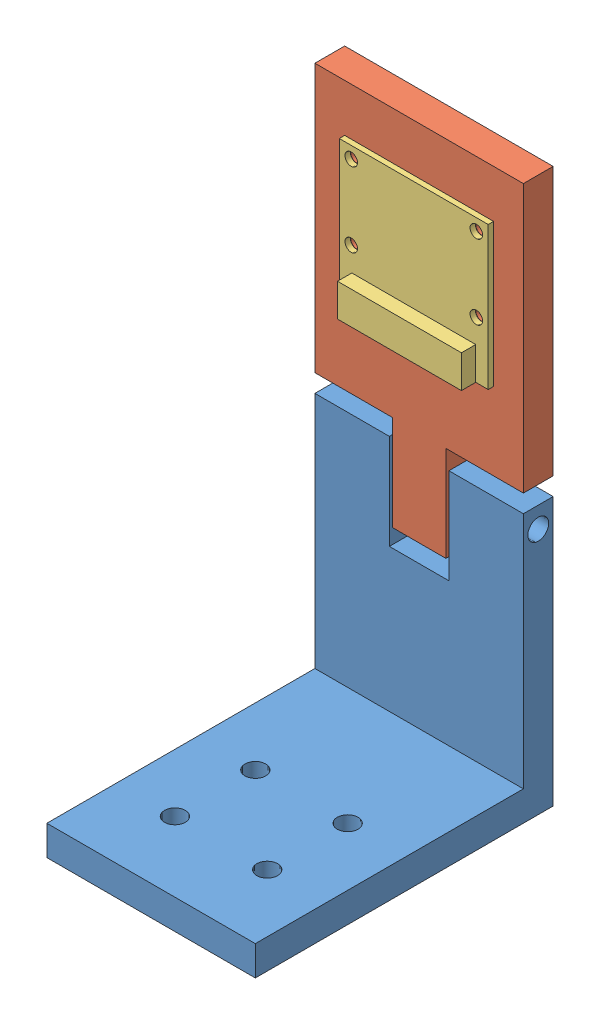
SolidWorks assembly Assem1, configuration Default. Lengths in mm.
Overall size (35 94.28 65.63).
10 component instances, 8 part files, 9 mates.
Components (placement in the parent):
- Camera mount bottom-1: Camera mount bottom [Default] at (-23.7366 -18.3036 25.44) size (35 45 50)
- Part3^New Camera Mount-1: Part3^New Camera Mount [Default] at (-16.9354 -4.185 34.7622) x (0 -0.265804 -0.964027) z (1 0 0) size (21.03 60.13 35) (virtual)
- RasPi_Camera-1: RasPi_Camera [FOV] at (-6.2366 52.1964 -20.1117) x (1 0 0) z (0 1 0) size (25 8.25 24)
  - RasPi_Camera_Board-1: RasPi_Camera_Board [Standard] at (0 -0.5517 0) x (-1 0 0) z (0 0 -1) size (25 3.5 24)
  - OVA5647-2: OVA5647 [FOV] at (0.0315 -0.3517 0.0586) size (8 5.3 16.75)
    - OVA5647-1: OVA5647 [Standard] at (0.32 0 -0.175) size (8 0.68 8)
    - OVA5647_Housing-1: OVA5647_Housing [Standard] at origin size (8 3.95 8)
    - OVA5647_IR-Glas-1: OVA5647_IR-Glas [Standard] at (0 0.95 0) x (-1 0 0) z (0 0 1) size (6.3 0.35 6.3)
    - OVA5647_Lens-1: OVA5647_Lens [FOV] at (0 3.95 0) size (6 3.35 6)
    - OVA5647_Pigtail-1: OVA5647_Pigtail [Standard] at origin size (8 1.3 16.75)
Mates (geometry in assembly coordinates):
- InPlace1: in place: plane of Camera mount bottom-1 through (-11.2366 26.6964 -24.56) normal (1 0 0); plane of ? through (-11.2366 0 0) normal (1 0 0); moOrthogonalPlaneRef_w of Camera mount bottom-1 through (-11.2366 26.6964 -24.56) normal (1 0 0); plane of ? through (-11.2366 0 0) normal (0 1 0); plane of Camera mount bottom-1 through (-11.2366 26.6964 -24.56) normal (1 0 0); plane of ? through (-11.2366 0 0) normal (0 0 -1); plane of Camera mount bottom-1 through (-11.2366 26.6964 -24.56) normal (1 0 0); unknown of Part3^New Camera Mount-1
- Coincident1: coincident aligned: plane of ?; plane of ?
- Coincident2: coincident aligned: moOrthogonalPlaneRef_w of Camera mount bottom-1 through (-11.2366 -18.3036 25.44) normal (0 1 0); plane of Part3^Assem1-1
- Coincident3: coincident anti-aligned: moOrthogonalPlaneRef_w of Camera mount bottom-1 through (-11.2366 -18.3036 25.44) normal (0 0 1); plane of Part3^Assem1-1
- Concentric1: concentric aligned: cylinder of Camera mount bottom-1 through (11.2634 23.1964 -22.06) axis (-1 0 0) radius 1.75; cylinder of Part3^Assem1-1 through (11.2644 23.1964 -22.06) axis (-1 0 0) radius 1.75
- Width2: width anti-aligned: plane of Camera mount bottom-1 through (-1.2366 26.6964 -19.56) normal (-1 0 0); plane of Part3^Assem1-1 through (-11.2366 26.6964 -24.56) normal (1 0 0); plane of Camera mount bottom-1 through (-1.7366 13.6964 -94.8878) normal (1 0 0); plane of Part3^Assem1-1 through (-10.7366 29.6964 -94.8878) normal (-1 0 0)
- Coincident4: coincident anti-aligned: plane of Part3^Assem1-1 through (-16.9354 -4.185 -19.56) normal (0 0 1); plane of RasPi_Camera-1/RasPi_Camera_Board-1 through (-6.2366 52.1964 -19.56) normal (0 0 -1)
- Concentric2: concentric anti-aligned: cylinder of Part3^Assem1-1 through (4.2634 64.6964 -40.192) axis (0 0 1) radius 1; cylinder of RasPi_Camera-1/RasPi_Camera_Board-1 through (4.2634 64.6964 -18.66) axis (0 0 -1) radius 1.05
- Concentric3: concentric anti-aligned: cylinder of Part3^Assem1-1 through (-16.7366 52.1964 -40.192) axis (0 0 1) radius 1; cylinder of RasPi_Camera-1/RasPi_Camera_Board-1 through (-16.7366 52.1964 -18.66) axis (0 0 -1) radius 1.05
